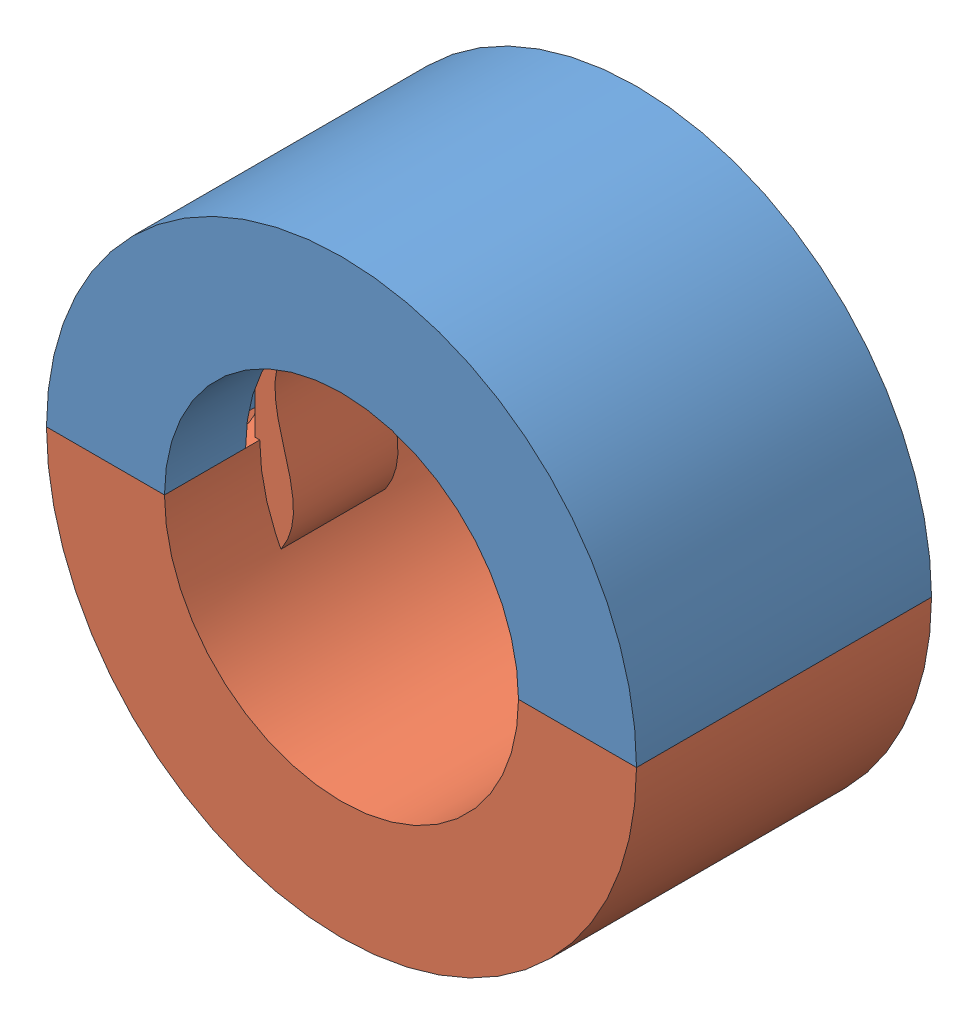
SolidWorks assembly Assem8-18, configuration Default. Lengths in mm.
Overall size (50 50 25).
2 component instances, 2 part files, 3 mates.
Components (placement in the parent):
- small_2nd half-try-8-16-1: small_2nd half-try-8-16 [Default] at (-50.5014 18.6201 7.2048) size (50 29.41 25)
- small_half-try-8-16-1: small_half-try-8-16 [Default] at (-50.5014 18.6201 7.2048) x (1 0 0) z (0 0 -1) size (50 32.03 25)
Mates (geometry in assembly coordinates):
- Coincident1: coincident anti-aligned: plane of small_2nd half-try-8-16-1 through (-35.5014 18.6201 19.7048) normal (0 -1 0); plane of small_half-try-8-16-1 through (-35.5014 18.6201 -5.2952) normal (0 1 0)
- Coincident2: coincident aligned: plane of small_2nd half-try-8-16-1 through (-50.5014 18.6201 19.7048) normal (0 0 1); plane of small_half-try-8-16-1 through (-50.5014 18.6201 19.7048) normal (0 0 1)
- Concentric1: concentric anti-aligned: cylinder of small_2nd half-try-8-16-1 through (-50.5014 18.6201 19.7048) axis (0 0 -1) radius 25; cylinder of small_half-try-8-16-1 through (-50.5014 18.6201 -5.2952) axis (0 0 1) radius 25
